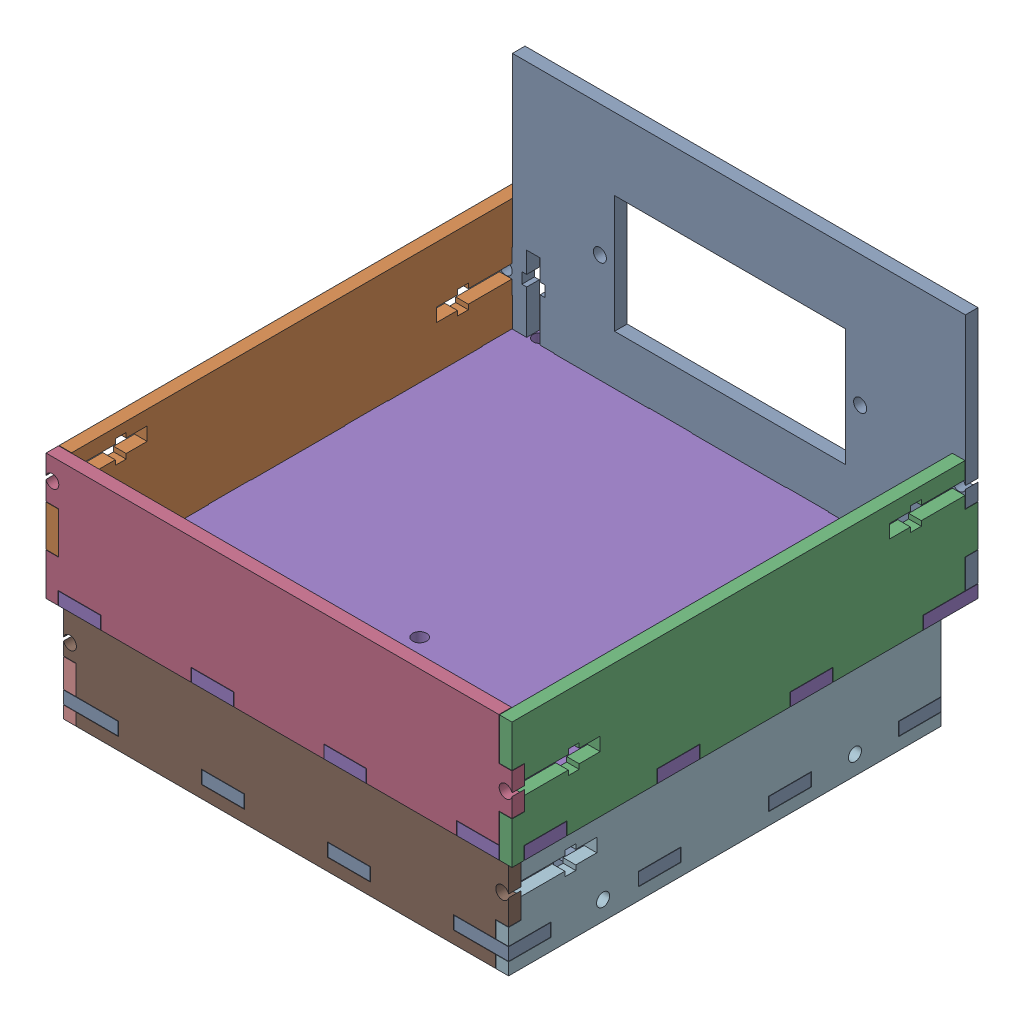
SolidWorks assembly Food-Plate, configuration Predeterminado. Lengths in mm.
Overall size (111 84.7 111).
3 component instances, 3 part files, 4 mates.
Components (placement in the parent):
- Pieza1-plate-1: Pieza1-plate [Predeterminado] at (-25.2008 92.2421 -37.5266) size (111 63 111)
- weight sensor FHDA-3: weight sensor FHDA [Default] at (-25.2008 79.8921 -37.0266) x (0 0 -1) z (1 0 0) size (82 15.5 15)
- Pieza2-plate-4: Pieza2-plate [Predeterminado] at (-25.4377 70.5421 -36.952) size (106 23 103)
Mates (geometry in assembly coordinates):
- Concéntrica4: concentric: circle of Pieza1-plate-1; circle of load sensor FHDA-3
- Tangente1: tangent: plane of Pieza1-plate-1 through (-25.2008 86.2421 -37.5266) normal (0 -1 0); circle of load sensor FHDA-3
- Concéntrica5: concentric: circle of load sensor FHDA-3; circle of Pieza2-plate-4
- Tangente2: tangent: circle of load sensor FHDA-3; plane of Pieza2-plate-4 through (-25.4377 73.5421 -36.952) normal (0 1 0)
